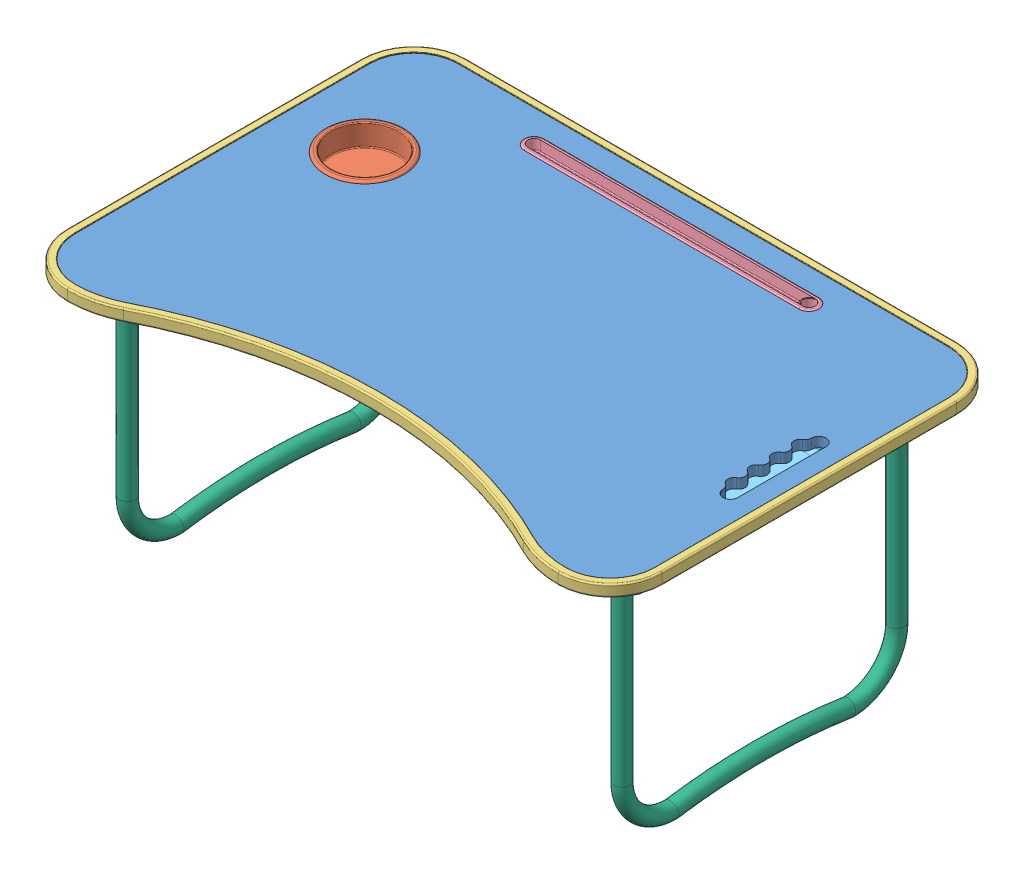
SolidWorks assembly BedDesk, configuration Default. Lengths in mm.
Overall size (606 274.4 406).
29 component instances, 8 part files, 28 mates.
Components (placement in the parent):
- deskPlate-1: deskPlate [Default] at origin size (600 20 400)
- cupholder-1: cupholder [Default] at (-220 -17 -70) size (80 24 80)
- deskEdge-1: deskEdge [Default] at origin size (606 12.17 406)
- penslot-1: penslot [Default] at (0 -6.5 -162.5) size (300 12.5 20)
- drawer-1: drawer [Default] at (160 -30 0) x (-1 0 0) z (0 0 -1) size (255 25 160)
- LegAsm-1: LegAsm [Default] at (-252 -9 0.015) x (0 0 -1) z (1 0 0) size (319.97 267.4 60)
  - leg-1: leg [Default] at origin size (309.97 258.4 16.94)
  - connectionNotch-1: connectionNotch [Default] at (139.985 4 27) x (-1 0 0) z (0 0 1) size (40 27 60)
  - connectionNotch-2: connectionNotch [Default] at (-139.985 4 27) x (-1 0 0) z (0 0 1) size (40 27 60)
  - fastener-1: fastener [Default] at (-123.985 -2 -18) x (-1 0 0) z (0 0 -1) size (5 11 5)
  - fastener-2: fastener [Default] at (-123.985 -2 22) size (5 11 5)
  - fastener-3: fastener [Default] at (-155.985 -2 22) size (5 11 5)
  - fastener-4: fastener [Default] at (-155.985 -2 -18) size (5 11 5)
  - fastener-5: fastener [Default] at (155.985 -2 22) size (5 11 5)
  - fastener-6: fastener [Default] at (123.985 -2 22) size (5 11 5)
  - fastener-7: fastener [Default] at (155.985 -2 -18) size (5 11 5)
  - fastener-8: fastener [Default] at (123.985 -2 -18) size (5 11 5)
- LegAsm-2: LegAsm [Default] at (252 -9 0.015) x (0 0 1) z (-1 0 0) size (319.97 267.4 60)
  - leg-1: leg [Default] at origin size (309.97 258.4 16.94)
  - connectionNotch-1: connectionNotch [Default] at (139.985 4 27) x (-1 0 0) z (0 0 1) size (40 27 60)
  - connectionNotch-2: connectionNotch [Default] at (-139.985 4 27) x (-1 0 0) z (0 0 1) size (40 27 60)
  - fastener-1: fastener [Default] at (-123.985 -2 -18) x (-1 0 0) z (0 0 -1) size (5 11 5)
  - fastener-2: fastener [Default] at (-123.985 -2 22) size (5 11 5)
  - fastener-3: fastener [Default] at (-155.985 -2 22) size (5 11 5)
  - fastener-4: fastener [Default] at (-155.985 -2 -18) size (5 11 5)
  - fastener-5: fastener [Default] at (155.985 -2 22) size (5 11 5)
  - fastener-6: fastener [Default] at (123.985 -2 22) size (5 11 5)
  - fastener-7: fastener [Default] at (155.985 -2 -18) size (5 11 5)
  - fastener-8: fastener [Default] at (123.985 -2 -18) size (5 11 5)
Mates (geometry in assembly coordinates):
- Coincident1: coincident aligned: plane of deskPlate-1 through (0 0 0) normal (0 0 1)
- Coincident2: coincident aligned: plane of deskPlate-1 through (0 0 0) normal (0 1 0)
- Coincident3: coincident aligned: plane of deskPlate-1 through (0 0 0) normal (1 0 0)
- Coincident4: coordinate: point of deskPlate-1
- Coincident5: coincident anti-aligned: plane of deskPlate-1 through (-250 5 -150) normal (0 1 0); plane of cupholder-1 through (-220 5 -70) normal (0 -1 0)
- Concentric1: concentric aligned: cylinder of deskPlate-1 through (-220 5 -70) axis (0 -1 0) radius 35; cylinder of cupholder-1 through (-220 -15 -70) axis (0 -1 0) radius 35
- Parallel1: parallel aligned: plane of deskPlate-1 through (0 0 0) normal (0 0 1); plane of cupholder-1 through (-220 -17 -70) normal (0 0 1)
- Parallel2: parallel aligned: plane of deskPlate-1 through (0 0 0) normal (1 0 0); plane of cupholder-1 through (-220 -17 -70) normal (1 0 0)
- Coincident7: coincident anti-aligned: plane of deskPlate-1 through (-250 5 -150) normal (0 1 0); plane of deskEdge-1 through (-250 5 -150) normal (0 -1 0)
- Concentric2: concentric aligned: cylinder of deskPlate-1 through (-250 5 150) axis (0 -1 0) radius 50; cylinder of deskEdge-1 through (-250 5 150) axis (0 -1 0) radius 50
- Coincident8: coincident aligned: plane of deskPlate-1 through (0 0 0) normal (0 0 1); plane of deskEdge-1 through (0 0 0) normal (0 0 1)
- Coincident9: coincident anti-aligned: plane of deskPlate-1 through (-250 5 -150) normal (0 1 0); plane of penslot-1 through (-140 5 -162.5) normal (0 -1 0)
- Concentric3: concentric aligned: cylinder of deskPlate-1 through (-140 5 -162.5) axis (0 -1 0) radius 7.5; cylinder of penslot-1 through (-140 -5 -162.5) axis (0 -1 0) radius 7.5
- Coincident10: coincident aligned: plane of deskPlate-1 through (0 0 0) normal (1 0 0); plane of penslot-1 through (0 -6.5 -162.5) normal (1 0 0)
- Parallel4: parallel aligned: plane of deskPlate-1 through (0 0 0) normal (0 0 1); plane of penslot-1 through (0 -6.5 -162.5) normal (0 0 1)
- Coincident18: coincident anti-aligned: plane of deskPlate-1 through (-250 -5 -150) normal (0 -1 0); plane of drawer-1 through (160 -5 0) normal (0 1 0)
- Coincident19: coincident anti-aligned: plane of deskPlate-1 through (0 0 -75) normal (0 0 1); plane of drawer-1 through (280 -5 -75) normal (0 0 -1)
- LimitDistance1: limit distance = 0 mm anti-aligned: plane of deskPlate-1 through (280 -15 -70) normal (1 0 0); plane of drawer-1 through (280 -5 -80) normal (-1 0 0)
- Parallel9: parallel anti-aligned: plane of drawer-1 through (160 -30 0) normal (-1 0 0)
- Coincident23: coincident anti-aligned: plane of deskPlate-1 through (0 0 0) normal (0 0 1); plane of drawer-1 through (160 -30 0) normal (0 0 -1)
- Concentric5: concentric aligned: cylinder of deskPlate-1 through (-270 0 156) axis (0 -1 0) radius 1.5; cylinder of LegAsm-1/fastener-4 through (-270 0 156) axis (0 -1 0) radius 1.49
- Coincident25: coincident anti-aligned: plane of deskPlate-1 through (-250 -5 -150) normal (0 -1 0); plane of LegAsm-1/connectionNotch-2 through (-265 -5 140) normal (0 1 0)
- Parallel11: parallel aligned: plane of deskPlate-1 through (0 0 0) normal (0 1 0); plane of LegAsm-1 through (-252 -9 0.015) normal (0 1 0)
- Parallel12: parallel anti-aligned: plane of deskPlate-1 through (0 0 0) normal (0 0 1); plane of LegAsm-1 through (-252 -9 0.015) normal (0 0 -1)
- Parallel13: parallel aligned: plane of LegAsm-2 through (252 -9 0.015) normal (0 0 1)
- Coincident29: coincident anti-aligned: plane of deskPlate-1 through (-250 -5 -150) normal (0 -1 0); plane of LegAsm-2/connectionNotch-1 through (265 -5 140) normal (0 1 0)
- Concentric6: concentric aligned: cylinder of deskPlate-1 through (270 0 156) axis (0 -1 0) radius 1.5; cylinder of LegAsm-2/fastener-7 through (270 0 156) axis (0 -1 0) radius 1.49
- Parallel14: parallel aligned: plane of deskPlate-1 through (0 0 0) normal (0 1 0); plane of LegAsm-2 through (252 -9 0.015) normal (0 1 0)
